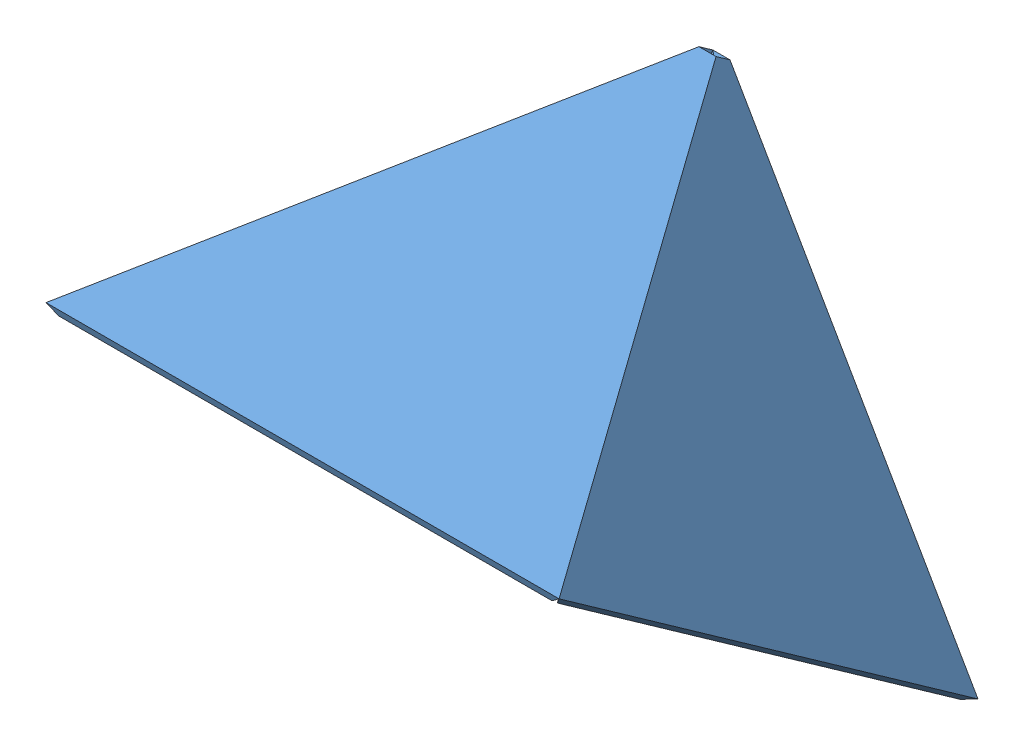
SolidWorks assembly Pyramide, configuration Défaut. Lengths in mm.
Overall size (300 342.99 365.01).
4 component instances, 1 part files, 8 mates.
Components (placement in the parent):
- FacePyramideFini-1: FacePyramideFini [Défaut] at (-21.8702 -119.0529 297.5) size (300 251.15 5)
- FacePyramideFini-2: FacePyramideFini [Défaut] at (-166.0512 -29.0907 424.7257) x (0 -0.57735 -0.816497) z (0.816497 -0.471405 0.333333) size (300 251.15 5)
- FacePyramideFini-3: FacePyramideFini [Défaut] at (133.9488 -35.8099 415.2233) x (0 0.57735 0.816497) z (-0.816497 -0.471405 0.333333) size (300 251.15 5)
- FacePyramideFini-4: FacePyramideFini [Défaut] at (-10.2323 54.1522 542.449) x (-1 0 0) z (0 -0.942809 -0.333333) size (300 251.15 5)
Mates (geometry in assembly coordinates):
- Coïncidente9: coincident anti-aligned: line of FacePyramideFini-1 through (133.9488 -119.0529 297.5) axis (-0.5 0.866025 0); line of FacePyramideFini-3 through (-11.0512 132.0945 297.5) axis (0.5 -0.866025 0)
- Coïncidente10: coincident: point of FacePyramideFini-1; point of FacePyramideFini-3
- Coïncidente11: coincident anti-aligned: line of FacePyramideFini-1 through (-21.0512 132.0945 297.5) axis (-0.5 -0.866025 0); line of FacePyramideFini-2 through (-166.0512 -119.0529 297.5) axis (0.5 0.866025 0)
- Coïncidente12: coincident: point of FacePyramideFini-1; point of FacePyramideFini-2
- Coïncidente13: coincident anti-aligned: line of FacePyramideFini-3 through (136.0007 55.3369 541.5983) axis (-0.50684 0.284726 -0.813661); line of FacePyramideFini-4 through (-10.9828 137.9075 305.6366) axis (0.50684 -0.284726 0.813661)
- Coïncidente14: coincident: point of FacePyramideFini-3; point of FacePyramideFini-4
- Coïncidente15: coincident anti-aligned: line of FacePyramideFini-2 through (-20.9824 137.8282 305.6926) axis (-0.493113 -0.292651 0.819265); line of FacePyramideFini-4 through (-163.9852 52.9594 543.2794) axis (0.493113 0.292651 -0.819265)
- Perpendiculaire1: perpendicular: line of FacePyramideFini-3 through (-11.0512 137.868 305.665) axis (0 -0.57735 -0.816497); line of FacePyramideFini-4 through (-21.0512 137.868 305.665) axis (1 0 0)
